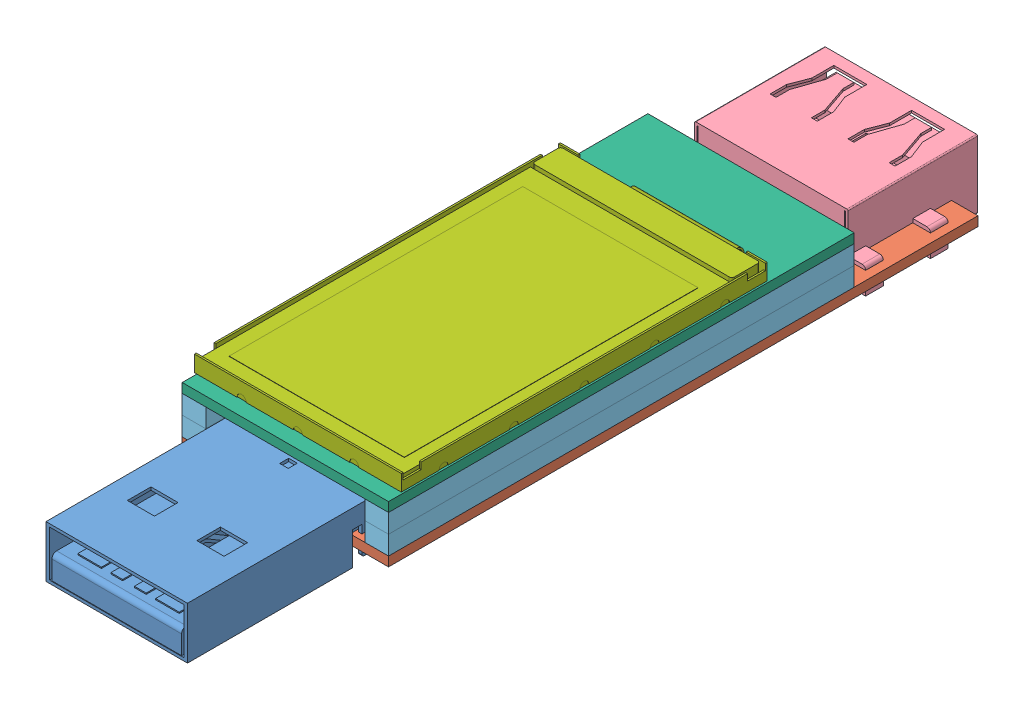
SolidWorks assembly Flash Power Recorder, configuration 默认. Lengths in mm.
Overall size (19.04 7.61 66.52).
8 component instances, 7 part files, 13 mates.
Components (placement in the parent):
- USB-AM-5pin-VOOC-1: USB-AM-5pin-VOOC [默认] at (-12 -0.9605 71.1683) x (0 0 -1) z (1 0 0) size (19 4.4 12)
- 底部PCB-1: 底部PCB [默认] at (-12.0452 0.8295 67.7353) x (0 0 1) z (0 -1 0) size (50 17.5 0.8)
- USB Type C Port (SMD Type)-1: USB Type C Port (SMD Type) [Default] at (-9.4878 2.4345 58.0719) x (0 0 1) z (0 -1 0) size (8.94 7.9 4.2)
- USB-AF-5pin-VOOC-2: USB-AF-5pin-VOOC [默认] at (-0.3 1.3395 27.6455) x (1 0 0) z (0 0 -1) size (16 5.8 12)
- Middle layer frame-1: Middle layer frame [默认] at (-12.0452 0.8295 67.7353) x (0 0 -1) z (0 1 0) size (39.5 17.5 1.6)
- Middle layer frame-2: Middle layer frame [默认] at (-12.0452 2.4295 67.7353) x (0 0 -1) z (0 1 0) size (39.5 17.5 1.6)
- Top layer PCB-1: Top layer PCB [默认] at origin size (17.5 0.8 39.5)
- 1.14 TFT IPS - 13P - Flat Flush Mount-1: 1.14 TFT IPS - 13P - Flat Flush Mount [默认] at (-6.5257 4.9819 54.2594) x (0 0 1) z (0 1 0) size (31.66 17.55 1.59)
Mates (geometry in assembly coordinates):
- 重合13: coincident: plane of assembly; plane of assembly; plane of USB-AM-5pin-VOOC-1 through (-12 0.8295 71.1683) normal (0 -1 0); plane of 底部PCB-1 through (-12.0452 0.8295 67.7353) normal (0 1 0)
- 重合15: coincident: plane of assembly; plane of assembly; plane of 底部PCB-1 through (-12.0452 0.8295 67.7353) normal (0 1 0); plane of USB Type C Port (SMD Type)-1 through (-16.7878 0.8295 53.6019) normal (0 -1 0)
- 重合17: coincident: plane of assembly; plane of assembly; plane of 底部PCB-1 through (-12.0452 0.8295 67.7353) normal (0 1 0); plane of USB-AF-5pin-VOOC-2 through (-0.3 0.8295 27.6455) normal (0 -1 0)
- 平行10: parallel: plane of assembly; plane of assembly; plane of USB-AM-5pin-VOOC-1 through (-1 2.8395 68.1683) normal (0 0 -1); plane of USB-AF-5pin-VOOC-2 through (-12.7 4.3395 29.6455) normal (0 0 1)
- 距离3: distance = 2 mm: plane of assembly; plane of assembly; plane of USB-AM-5pin-VOOC-1 through (-0.5 -1.2605 68.7683) normal (1 0 0); plane of USB-AF-5pin-VOOC-2 through (1.5 -1.0605 22.6455) normal (1 0 0)
- 距离4: distance = 2.75 mm: plane of assembly; plane of assembly; plane of 底部PCB-1 through (2.25 0.0295 20.8633) normal (1 0 0); plane of USB-AM-5pin-VOOC-1 through (-0.5 -1.2605 68.7683) normal (1 0 0)
- 在位2: in place: plane of 底部PCB-1 through (-12.0452 0.8295 67.7353) normal (0 1 0); plane of ? through (0 0.8295 0) normal (0 1 0); moOrthogonalPlaneRef_w of 底部PCB-1 through (-12.0452 0.8295 67.7353) normal (0 1 0); plane of ? through (0 0.8295 0) normal (0 0 -1); plane of 底部PCB-1 through (-12.0452 0.8295 67.7353) normal (0 1 0); plane of ? through (0 0.8295 0) normal (1 0 0); plane of 底部PCB-1 through (-12.0452 0.8295 67.7353) normal (0 1 0); unknown of Middle layer frame-1
- 重合22: coincident: plane of assembly; plane of assembly; plane of 底部PCB-1; plane of Middle layer frame-1
- 重合23: coincident: plane of assembly; plane of assembly; moOrthogonalPlaneRef_w of 底部PCB-1 through (-12.0452 0.8295 67.7353) normal (-1 0 0); plane of Middle layer frame-1 through (-12.0452 0.8295 67.7353) normal (-1 0 0)
- 重合24: coincident: plane of assembly; plane of assembly; moOrthogonalPlaneRef_w of 底部PCB-1 through (-12.0452 0.8295 67.7353) normal (0 0 1); plane of Middle layer frame-1 through (-12.0452 0.8295 67.7353) normal (0 0 -1)
- 重合18: coincident: plane of assembly; plane of assembly; plane of Top layer PCB-1 through (0 4.8295 0) normal (0 1 0); plane of 1.14 TFT IPS - 13P - Flat Flush Mount-1 through (-0.3408 4.8295 52.6084) normal (0 -1 0)
- 平行11: parallel: plane of assembly; plane of assembly; plane of Top layer PCB-1 through (-15.25 4.8295 70.8633) normal (-1 0 0); plane of 1.14 TFT IPS - 13P - Flat Flush Mount-1 through (-15.3014 5.1343 69.7788) normal (-1 0 0)
- 重合20: coincident: line of assembly; plane of assembly; line of Top layer PCB-1 through (2.25 4.0295 70.8633) axis (0 0 -1); plane of 1.14 TFT IPS - 13P - Flat Flush Mount-1 through (2.25 5.1343 38.74) normal (1 0 0)
